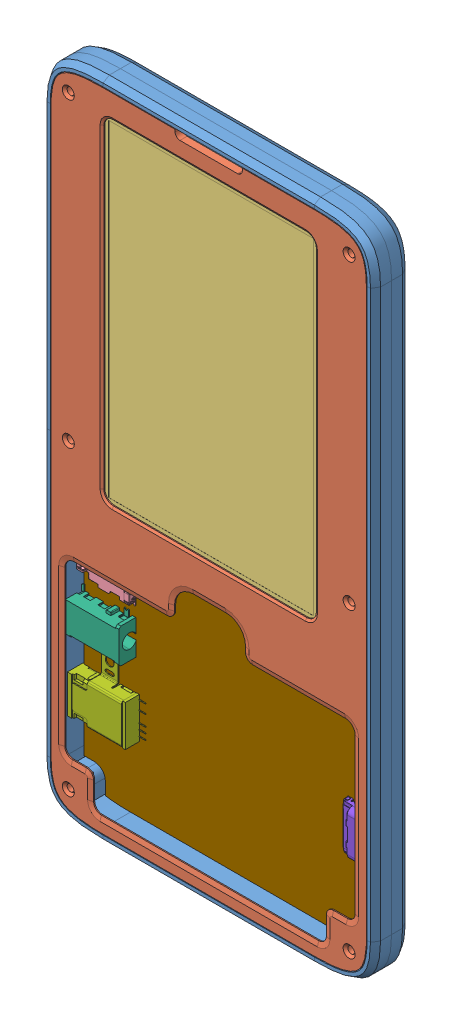
SolidWorks assembly betrusted-dvt1-top, configuration Default. Lengths in mm.
Overall size (73.61 141.12 8.55).
12 component instances, 9 part files, 17 mates.
Components (placement in the parent):
- bottom-case-1: bottom-case [Default] at origin size (73.61 141.12 8.37)
- front-bezel-1: front-bezel [Default] at origin size (73.61 141.12 8.32)
- sharp_ls032b7dd02-folded-cable-1: sharp_ls032b7dd02-folded-cable [Default] at (-23.51 -12.27 2.51) x (1 0 0) z (0 -1 0) size (47.02 1.69 76.9)
- CUI_SJ-43504-SMT-TR-1: CUI_SJ-43504-SMT-TR [Default] at (-32.5 2.4521 -1) x (0 1 0) z (-1 0 0) size (9.1 5 14)
- CX90B1-24P_4800497000_3D-1: CX90B1-24P_4800497000_3D [Default] at (7.1016 -8.5889 0.17) x (0 1 0) z (1 0 0) size (8.95 3.77 8.17)
  - CX90B1-24P_4800497000_3D.stp-1: CX90B1-24P_4800497000_3D.stp [Default] at origin size (8.95 3.77 8.17)
    - CX90B1-24P.stp-1: CX90B1-24P.stp [Default] at (-4.592 -1.505 24.2234) size (8.95 3.77 8.17)
- CUI_SJ-43504-SMT-TR-2: CUI_SJ-43504-SMT-TR [Default] at (-32.5 -23.5112 -2.4) x (0 -1 0) z (-1 0 0) size (9.1 5 14)
- CUI_DEVICES_SJ-43615TS-SMT-TR-1: CUI_DEVICES_SJ-43615TS-SMT-TR [Default] at (-32.6 -33.7227 -0.4) x (0 1 0) z (-1 0 0) size (8.6 5.7 14)
- CUI_DEVICES_SJ-3542AS-SMT-TR-67-1: CUI_DEVICES_SJ-3542AS-SMT-TR-67 [Default] at (-49.85 -43.7635 1.35) size (16.15 13.77 5.6)
- c-1-2295018-2-b-3d-1: c-1-2295018-2-b-3d [Default] at (31.65 -44.9456 -1.15) x (0 1 0) z (1 0 0) size (12.14 3.6 8.1)
- pcb-max-extent-1: pcb-max-extent [Default] at origin size (73.61 141.12 8.32)
Mates (geometry in assembly coordinates):
- Coincident1: coincident anti-aligned: plane of front-bezel-1 through (0 0 3.1) normal (0 0 -1); plane of sharp_ls032b7dd02-folded-cable-1 through (-23.51 -12.27 3.1) normal (0 0 1)
- Width1: width aligned: plane of front-bezel-1 through (23.71 -12.47 3.1) normal (-1 0 0); plane of front-bezel-1 through (-23.71 63.93 3.1) normal (1 0 0); plane of sharp_ls032b7dd02-folded-cable-1 through (-23.51 -12.27 2.91) normal (-1 0 0); plane of sharp_ls032b7dd02-folded-cable-1 through (23.51 -12.27 2.91) normal (1 0 0)
- Width2: width anti-aligned: plane of sharp_ls032b7dd02-folded-cable-1 through (-23.51 63.73 2.91) normal (0 1 0); plane of sharp_ls032b7dd02-folded-cable-1 through (-23.51 -12.27 2.91) normal (0 -1 0); plane of front-bezel-1 through (23.71 63.93 3.1) normal (0 -1 0); plane of front-bezel-1 through (-23.71 -12.47 3.1) normal (0 1 0)
- Coincident2: coincident aligned: plane of bottom-case-1 through (-34.5 0 0) normal (-1 0 0); plane of CUI_SJ-43504-SMT-TR-1 through (-34.5 2.4521 -1) normal (-1 0 0)
- Parallel1: parallel anti-aligned: plane of CUI_SJ-43504-SMT-TR-1 through (-20.5 -0.6979 -3.1) normal (0 0 -1); plane of pcb-max-extent-1 through (31.3853 -59.8112 -1.8) normal (0 0 1)
- Coincident9: coincident anti-aligned: plane of CUI_SJ-43504-SMT-TR-1 through (-22.3 -1.9479 -1.8) normal (0 0 -1); plane of pcb-max-extent-1 through (31.3853 -59.8112 -1.8) normal (0 0 1)
- Parallel2: parallel: plane of bottom-case-1 through (30.725 -65.8 -2.6) normal (0 0 1); plane of CX90B1-24P_4800497000_3D-1/CX90B1-24P_4800497000_3D.stp-1/CX90B1-24P.stp-1 through (26.15 -16.5053 -1.78) normal (0 0 -1)
- Coincident4: coincident anti-aligned: plane of bottom-case-1 through (31.7 59 2.1) normal (-1 0 0); plane of CX90B1-24P_4800497000_3D-1/CX90B1-24P_4800497000_3D.stp-1/CX90B1-24P.stp-1 through (31.7 -26.1245 -2.2779) normal (1 0 0)
- Distance2: distance = 0.8 mm: plane of CX90B1-24P_4800497000_3D-1/CX90B1-24P_4800497000_3D.stp-1/CX90B1-24P.stp-1 through (23.55 -12.2159 -1.8) normal (0 0 -1); plane of bottom-case-1 through (30.725 -65.8 -2.6) normal (0 0 1)
- Coincident5: coincident aligned: plane of bottom-case-1 through (-34.5 -59 0) normal (-1 0 0); plane of CUI_SJ-43504-SMT-TR-2 through (-34.5 -23.5112 -2.4) normal (-1 0 0)
- Distance4: distance = 0.8 mm: plane of CUI_SJ-43504-SMT-TR-2 through (-21.5 -27.0112 -1.8) normal (0 0 -1); plane of bottom-case-1 through (30.725 -65.8 -2.6) normal (0 0 1)
- Coincident6: coincident aligned: plane of bottom-case-1 through (-34.5 -59 0) normal (-1 0 0); plane of CUI_DEVICES_SJ-43615TS-SMT-TR-1 through (-34.5 -33.7227 -0.4) normal (-1 0 0)
- Distance5: distance = 0.8 mm: plane of CUI_DEVICES_SJ-43615TS-SMT-TR-1 through (-22.75 -37.8727 -1.8) normal (0 0 -1); plane of bottom-case-1 through (30.725 -65.8 -2.6) normal (0 0 1)
- Coincident7: coincident aligned: plane of bottom-case-1 through (-34.5 -59 0) normal (-1 0 0); plane of CUI_DEVICES_SJ-3542AS-SMT-TR-67-1 through (-34.5 -47.8935 -1) normal (-1 0 0)
- Distance6: distance = 0.8 mm: plane of CUI_DEVICES_SJ-3542AS-SMT-TR-67-1 through (-25.83 -41.6682 -1.8) normal (0 0 -1); plane of bottom-case-1 through (30.725 -65.8 -2.6) normal (0 0 1)
- Distance7: distance = 3 mm aligned: plane of c-1-2295018-2-b-3d-1 through (31.5 -47.9771 -1.5) normal (1 0 0); plane of bottom-case-1 through (34.5 59 0) normal (1 0 0)
- Distance8: distance = 0.8 mm: plane of c-1-2295018-2-b-3d-1 through (23.9552 -43.5956 -1.8) normal (0 0 -1); plane of bottom-case-1 through (30.725 -65.8 -2.6) normal (0 0 1)
